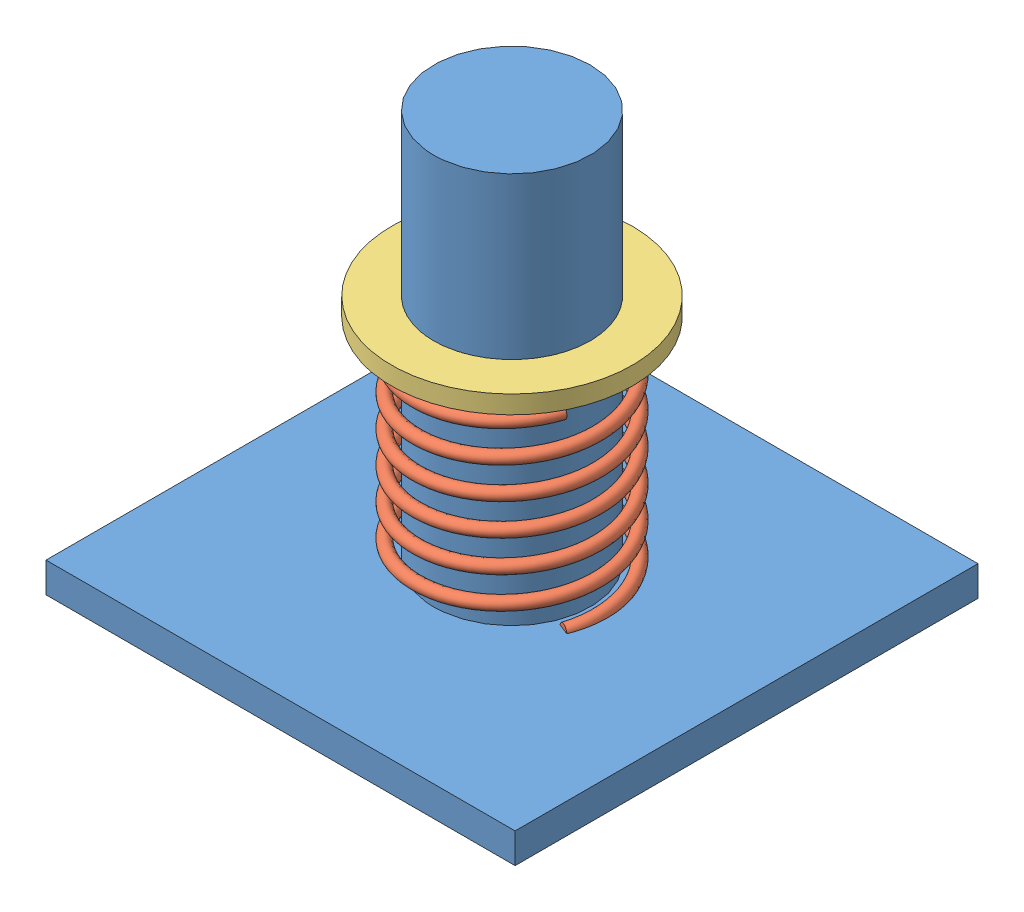
SolidWorks assembly Assem1, configuration Default. Lengths in mm.
Overall size (77.92 70 76.89).
3 component instances, 3 part files, 3 mates.
Components (placement in the parent):
- основа-1: основа [Default] at (30.0335 23.7312 70.8189) size (77.92 70 76.89)
- пружина-1: пружина [Default] at (30.0335 28.7312 70.8189) x (0.932181 0 0.361993) z (-0.361993 0 0.932181) size (32 33.53 36.95)
- кільце-1: кільце [Default] at (30.0335 64.0174 70.8189) x (0.970535 0 0.240961) z (-0.240961 0 0.970535) size (40 3 40)
Mates (geometry in assembly coordinates):
- Concentric1: concentric anti-aligned: cylinder of основа-1 through (30.0335 93.7312 70.8189) axis (0 -1 0) radius 13; line of пружина-1 through (30.0335 28.7312 70.8189) axis (0 1 0)
- Coincident2: coincident anti-aligned: plane of основа-1 through (30.0335 28.7312 70.8189) normal (0 1 0); plane of пружина-1 through (15.1195 28.7312 65.0274) normal (0 -1 0)
- Concentric2: concentric aligned: cylinder of основа-1 through (30.0335 93.7312 70.8189) axis (0 -1 0) radius 13; cylinder of кільце-1 through (30.0335 67.0174 70.8189) axis (0 -1 0) radius 13
